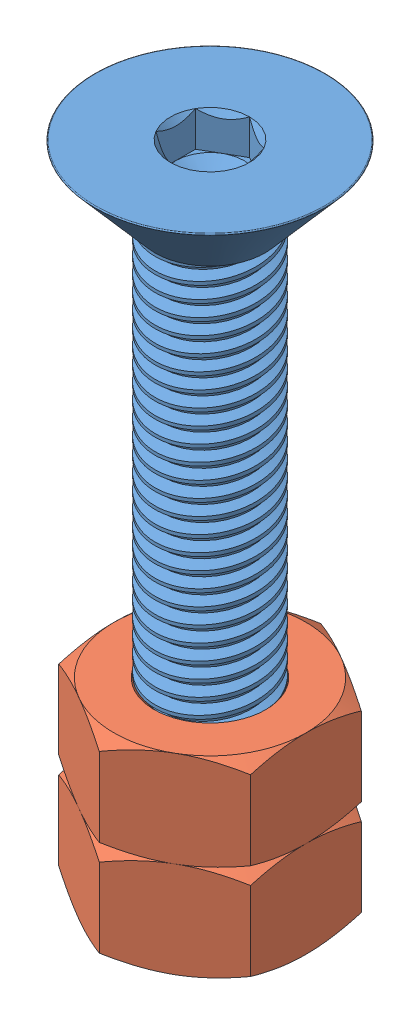
SolidWorks assembly 1-4_28_boltnut, configuration Default. Lengths in mm.
Overall size (13.37 38.65 13.37).
3 component instances, 2 part files, 5 mates.
Components (placement in the parent):
- 1_4-28_1_5-1: 1_4-28_1_5 [91253A313] at (-22.4376 -4.0894 20.77) x (1 0 0) z (0 1 0) size (13.37 13.37 38.41)
- 1-4_28_nut-1: 1-4_28_nut [90490A205] at (-22.4376 -32.5438 20.77) x (1 0 0) z (0 1 0) size (11.11 12.83 6.2)
- 1-4_28_nut-2: 1-4_28_nut [90490A205] at (-22.4376 -26.9875 20.77) x (1 0 0) z (0 1 0) size (11.11 12.83 6.2)
Mates (geometry in assembly coordinates):
- Coincident1: coincident aligned: plane of 1_4-28_1_5-1 through (-22.4376 -2.8824 -20.2124) normal (0 0 -1); plane of 1-4_28_nut-1 through (-27.9938 6.7414 -20.2124) normal (0 0 -1)
- Coincident2: coincident anti-aligned: plane of 1-4_28_nut-1 through (-27.9938 6.7414 -14.6561) normal (0 0 1); plane of 1-4_28_nut-2 through (-27.9938 6.7414 -14.6561) normal (0 0 -1)
- Concentric1: concentric aligned: circle of 1_4-28_1_5-1; circle of 1-4_28_nut-2
- Concentric2: concentric aligned: circle of 1_4-28_1_5-1; circle of 1-4_28_nut-1
- Coincident3: coincident aligned: plane of 1_4-28_1_5-1 through (-22.4376 0 20.77) normal (0 1 0); plane of assembly
